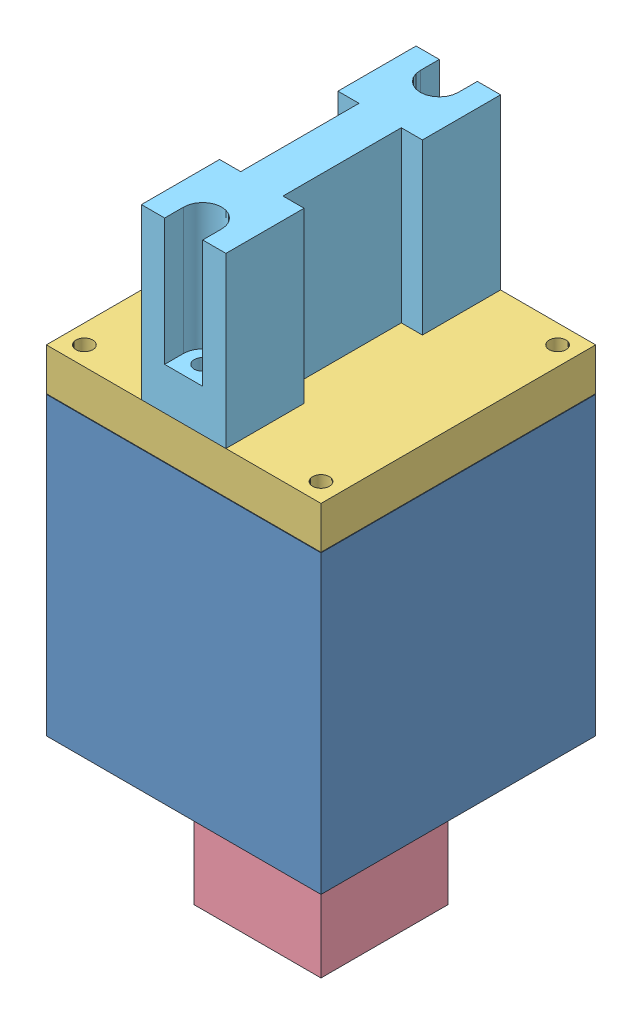
SolidWorks assembly Assem1, configuration Default. Lengths in mm.
Overall size (65 153.77 65).
5 component instances, 5 part files, 10 mates.
Components (placement in the parent):
- magnet_2-1: magnet_2 [Default] at (6.3165 15.9197 78.1881) size (65 70 65)
- magtnet_1-1: magtnet_1 [Default] at (24.8165 2.2956 61.6881) size (45 60 45)
- magtet_3-1: magtet_3 [Default] at (50.8165 86.062 57.6881) x (-1 0 0) z (0 0 1) size (65 45 65)
- magnet_4-1: magnet_4 [Default] at (24.8165 -17.7044 61.6881) size (30 20 30)
- magnet_5-1: magnet_5 [Default] at (28.8165 96.062 78.1881) size (20 40 65)
Mates (geometry in assembly coordinates):
- Coincident1: coincident anti-aligned: plane of magnet_2-1 through (62.3165 25.9197 22.1881) normal (-1 0 0); plane of magtnet_1-1 through (62.3165 42.2956 24.1881) normal (1 0 0)
- Coincident2: coincident anti-aligned: plane of magnet_2-1 through (15.3165 25.9197 69.1881) normal (0 0 -1); plane of magtnet_1-1 through (17.3165 42.2956 69.1881) normal (0 0 1)
- Coincident3: coincident aligned: plane of magnet_2-1 through (6.3165 85.9197 13.1881) normal (0 0 -1); plane of magtet_3-1 through (6.3165 96.062 13.1881) normal (0 0 -1)
- Coincident4: coincident aligned: plane of magnet_2-1 through (71.3165 85.9197 78.1881) normal (1 0 0); plane of magtet_3-1 through (71.3165 96.062 78.1881) normal (1 0 0)
- Coincident5: coincident anti-aligned: plane of magtnet_1-1 through (24.8165 2.2956 61.6881) normal (0 -1 0); plane of magnet_4-1 through (24.8165 2.2956 61.6881) normal (0 1 0)
- Coincident6: coincident aligned: plane of magtnet_1-1 through (54.8165 32.2956 61.6881) normal (1 0 0); plane of magnet_4-1 through (54.8165 2.2956 61.6881) normal (1 0 0)
- Coincident7: coincident aligned: plane of magtnet_1-1 through (24.8165 32.2956 61.6881) normal (0 0 1); plane of magnet_4-1 through (24.8165 2.2956 61.6881) normal (0 0 1)
- Coincident8: coincident anti-aligned: plane of magtet_3-1 through (50.8165 96.062 57.6881) normal (0 1 0); plane of magnet_5-1 through (28.8165 96.062 78.1881) normal (0 -1 0)
- Coincident9: coincident aligned: plane of magtet_3-1 through (6.3165 96.062 78.1881) normal (0 0 1); plane of magnet_5-1 through (28.8165 136.062 78.1881) normal (0 0 1)
- Concentric1: concentric aligned: cylinder of magtet_3-1 through (38.8165 89.062 73.6881) axis (0 1 0) radius 2.5; cylinder of magnet_5-1 through (38.8165 96.062 73.6881) axis (0 1 0) radius 2
